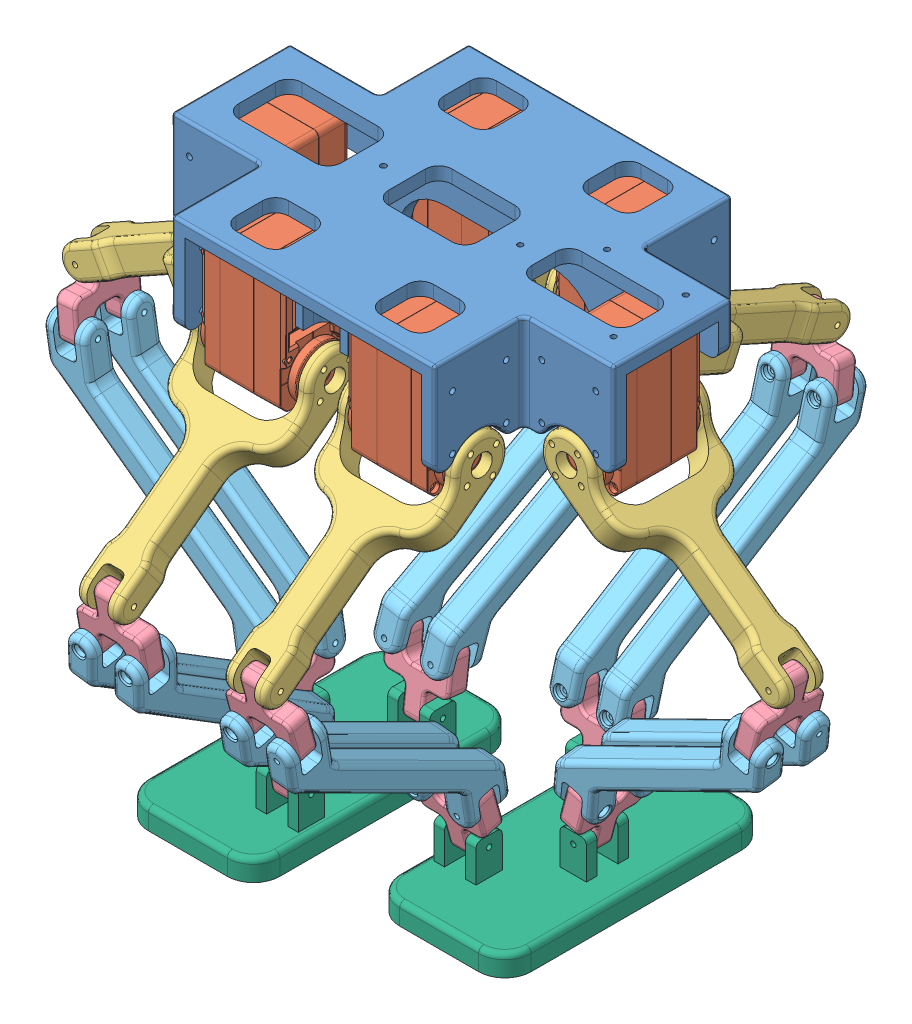
SolidWorks assembly bluebody, configuration Default. Lengths in mm.
Overall size (288.92 219.35 236.14).
42 component instances, 6 part files, 69 mates.
Components (placement in the parent):
- link0-1: link0 [Default] x (1 0 0) z (0 0 -1) size (168 59.68 113)
  - platform-v4-1: platform-v4 [Default] at (0 36.8 -17.5) x (-1 0 0) z (0 0 1) size (168 36.8 113)
  - Servo-LX-16A-1: Servo-LX-16A [Default] at (37.5 14.825 39.5) x (0 -1 0) z (0 0 1) size (54.66 37.3 26.46)
  - Servo-LX-16A-2: Servo-LX-16A [Default] at (-37.5 14.825 39.5) x (0 -1 0) z (0 0 -1) size (54.66 37.3 26.46)
  - Servo-LX-16A-3: Servo-LX-16A [Default] at (-67 14.825 -10) x (0 -1 0) z (1 0 0) size (54.66 37.3 26.46)
  - Servo-LX-16A-4: Servo-LX-16A [Default] at (-37.5 14.825 -39.5) x (0 -1 0) z (0 0 -1) size (54.66 37.3 26.46)
  - Servo-LX-16A-5: Servo-LX-16A [Default] at (37.5 14.825 -39.5) x (0 -1 0) z (0 0 1) size (54.66 37.3 26.46)
  - Servo-LX-16A-6: Servo-LX-16A [Default] at (67 14.825 -10) x (0 -1 0) z (1 0 0) size (54.66 37.3 26.46)
- link1-1: link1 [Default] at (27.9 -67.623 69.0097) x (0 0.602649 -0.798007) z (1 0 0) size (96 20 46.12)
- link1-2: link1 [Default] at (96.7069 -67.4082 0.4) x (-0.802358 0.596844 0) z (0 0 -1) size (96 20 46.12)
- link1-3: link1 [Default] at (27.9 -60.4464 -74.3013) x (0 0.411912 0.911223) z (-1 0 0) size (96 20 46.12)
- link1-4: link1 [Default] at (-27.9 -65.1405 -71.1258) x (0 0.535964 0.844241) z (-1 0 0) size (96 20 46.12)
- link1-5: link1 [Default] at (-99.9673 -63.3285 0.4) x (0.872961 0.48779 0) z (0 0 1) size (96 20 46.12)
- link1-6: link1 [Default] at (-27.9 -67.6197 69.0127) x (0 0.60256 -0.798074) z (1 0 0) size (96 20 46.12)
- link2-1: link2 [Default] at (27.9 -93.6553 100.3923) x (1 0 0) z (0 0.268825 -0.963189) size (25.2 28 7.6)
- link2-2: link2 [Default] at (128.2856 -93.2143 0.4) x (0 0 1) z (0.966195 -0.257814 0) size (25.2 28 7.6)
- link2-3: link2 [Default] at (27.9 -78.9149 -110.5714) x (1 0 0) z (0 -0.08941 -0.995995) size (25.2 28 7.6)
- link2-4: link2 [Default] at (-27.9 -88.5648 -104.657) x (1 0 0) z (0 -0.119223 -0.992868) size (25.2 28 7.6)
- link2-5: link2 [Default] at (-134.7236 -84.8335 0.4) x (0 0 -1) z (-0.99671 -0.08105 0) size (25.2 28 7.6)
- link2-6: link2 [Default] at (-27.9 -93.6878 100.5668) x (1 0 0) z (0 0.184429 -0.982846) size (25.2 28 7.6)
- link3-1: link3 [Default] at (8.3118 -142.3201 55.6635) x (0 0.268825 -0.963189) z (0.990297 -0.133854 -0.037359) size (76 94 10)
- link3-2: link3 [Default] at (25.9118 -142.3201 55.6635) x (0 -0.268825 0.963189) z (0.990297 -0.133854 -0.037359) size (76 94 10)
- link3-3: link3 [Default] at (83.7779 -143.6502 6.4272) x (-0.966195 0.257814 0) z (0.047194 0.176866 -0.983103) size (76 94 10)
- link3-4: link3 [Default] at (83.7779 -143.6502 -11.1728) x (0.966195 -0.257814 0) z (0.047194 0.176866 -0.983103) size (76 94 10)
- link3-5: link3 [Default] at (35.8148 -136.2784 -75.3013) x (0 -0.08941 -0.995995) z (-0.990297 0.138413 -0.012425) size (76 94 10)
- link3-6: link3 [Default] at (18.2148 -136.2784 -75.3013) x (0 -0.08941 -0.995995) z (-0.990297 0.138413 -0.012425) size (76 94 10)
- link3-7: link3 [Default] at (-21.2469 -144.8005 -67.6887) x (0 0.119223 0.992868) z (-0.985708 0.167261 -0.020085) size (76 94 10)
- link3-8: link3 [Default] at (-38.8469 -144.8005 -67.6887) x (0 0.119223 0.992868) z (-0.985708 0.167261 -0.020085) size (76 94 10)
- link3-9: link3 [Default] at (-99.9976 -141.7338 -16.4283) x (0.99671 0.08105 0) z (0.005869 -0.072177 0.997375) size (76 94 10)
- link3-10: link3 [Default] at (-99.9976 -141.7338 1.1717) x (0.99671 0.08105 0) z (0.005869 -0.072177 0.997375) size (76 94 10)
- link3-11: link3 [Default] at (-48.7039 -145.7078 60.2817) x (0 0.184429 -0.982846) z (0.985708 -0.165572 -0.031069) size (76 94 10)
- link3-12: link3 [Default] at (-31.1039 -145.7078 60.2817) x (0 0.184429 -0.982846) z (0.985708 -0.165572 -0.031069) size (76 94 10)
- bluefeet-1: bluefeet [Default] at (30.2265 -212.2498 -14.9766) x (0 0 -1) z (1 0 0) size (100 42.24 51.6) (flexible)
  - feet-1: feet [Default] at origin size (100 22 50)
  - link2-1: link2 [Default] at (-25.5376 19.9264 -14) x (0 0 -1) z (0.963189 0.268825 0) size (25.2 28 7.6)
  - link2-2: link2 [Default] at (0 19.9324 9.5156) x (1 0 0) z (0 -0.257814 0.966195) size (25.2 28 7.6)
  - link2-3: link2 [Default] at (25.1788 19.992 -14) x (0 0 -1) z (0.995995 -0.08941 0) size (25.2 28 7.6)
- bluefeet-2: bluefeet [Default] at (-56.0508 -219.3493 -5.6829) x (0 0 1) z (-1 0 0) size (100 42.29 51.6) (flexible)
  - feet-1: feet [Default] at origin size (100 22 50)
  - link2-1: link2 [Default] at (-25.2384 19.9857 -14) x (0 0 -1) z (0.992868 0.119223 0) size (25.2 28 7.6)
  - link2-2: link2 [Default] at (0 19.9934 9.1621) x (1 0 0) z (0 -0.08105 0.99671) size (25.2 28 7.6)
  - link2-3: link2 [Default] at (25.3689 19.9657 -14) x (0 0 -1) z (0.982846 -0.184429 0) size (25.2 28 7.6)
Mates (geometry in assembly coordinates):
- Coincident1: coincident aligned: plane of link0-1/platform-v4-1 through (0 0 17.5) normal (0 1 0)
- Coincident2: coincident anti-aligned: plane of link0-1/platform-v4-1 through (0 -36.8 17.5) normal (-1 0 0)
- Coincident4: coincident anti-aligned: plane of link0-1/platform-v4-1 through (0 -36.8 0) normal (0 0 -1)
- Concentric1: concentric aligned: cylinder of link0-1/Servo-LX-16A-5 through (46.6 -40.325 39.5) axis (1 0 0) radius 10; cylinder of link1-1 through (4.9 -40.325 39.5) axis (1 0 0) radius 4
- Distance1: distance = 0.9 mm anti-aligned: plane of link0-1/Servo-LX-16A-5 through (46 -29.3267 39.5) normal (1 0 0); plane of link1-1 through (46.9 -49.2688 82.8706) normal (-1 0 0)
- Concentric2: concentric anti-aligned: cylinder of link0-1/Servo-LX-16A-6 through (67 -40.325 -14.6) axis (0 0 1) radius 10; cylinder of link1-2 through (67 -40.325 23.4) axis (0 0 -1) radius 4
- Distance2: distance = 0.9 mm anti-aligned: plane of link1-2 through (110.4343 -48.954 -18.6) normal (0 0 1); plane of link0-1/Servo-LX-16A-6 through (86.9 -79.4276 -17.7) normal (0 0 -1)
- Concentric3: concentric anti-aligned: cylinder of link0-1/Servo-LX-16A-1 through (46.6 -40.325 -39.5) axis (1 0 0) radius 10; cylinder of link1-3 through (50.9 -40.325 -39.5) axis (-1 0 0) radius 4
- Distance3: distance = 0.9 mm anti-aligned: plane of link1-3 through (8.9 -39.4882 -83.7753) normal (1 0 0); plane of link0-1/Servo-LX-16A-1 through (9.8 -79.4276 -59.4) normal (-1 0 0)
- Concentric4: concentric aligned: cylinder of link0-1/Servo-LX-16A-2 through (-46.6 -40.325 -39.5) axis (-1 0 0) radius 10; cylinder of link1-4 through (-4.9 -40.325 -39.5) axis (-1 0 0) radius 4
- Distance4: distance = 0.9 mm anti-aligned: plane of link1-4 through (-8.9 -45.723 -83.453) normal (-1 0 0); plane of link0-1/Servo-LX-16A-2 through (-9.8 -79.4276 -19.6) normal (1 0 0)
- Concentric5: concentric aligned: cylinder of link0-1/Servo-LX-16A-3 through (-67 -40.325 19.1) axis (0 0 1) radius 10; cylinder of link1-5 through (-67 -40.325 -22.6) axis (0 0 1) radius 4
- Distance5: distance = 0.9 mm anti-aligned: plane of link1-5 through (-111.1864 -43.2503 -18.6) normal (0 0 1); plane of link0-1/Servo-LX-16A-3 through (-47.1 -79.4276 -17.7) normal (0 0 -1)
- Concentric6: concentric anti-aligned: cylinder of link1-6 through (-50.9 -40.325 39.5) axis (1 0 0) radius 4; cylinder of link0-1/Servo-LX-16A-4 through (-46.6 -40.325 39.5) axis (-1 0 0) radius 10
- Distance6: distance = 0.9 mm anti-aligned: plane of link1-6 through (-8.9 -49.264 82.8716) normal (-1 0 0); plane of link0-1/Servo-LX-16A-4 through (-9.8 -79.4276 59.4) normal (1 0 0)
- Concentric7: concentric aligned: cylinder of link1-1 through (4.9 -91.7289 100.9299) axis (1 0 0) radius 1; cylinder of link2-1 through (24.1 -91.7289 100.9299) axis (1 0 0) radius 1.15
- Distance7: distance = 0.2 mm anti-aligned: plane of link2-1 through (31.7 -94.6768 104.0524) normal (1 0 0); plane of link1-1 through (31.9 -49.2688 82.8706) normal (-1 0 0)
- Concentric8: concentric anti-aligned: cylinder of link1-2 through (128.8012 -91.2819 23.4) axis (0 0 -1) radius 1; cylinder of link2-2 through (128.8012 -91.2819 -3.4) axis (0 0 1) radius 1.15
- Distance8: distance = 0.2 mm anti-aligned: plane of link2-2 through (124.6141 -92.2346 -3.4) normal (0 0 -1); plane of link1-2 through (110.4343 -48.954 -3.6) normal (0 0 1)
- Concentric9: concentric anti-aligned: cylinder of link1-3 through (50.9 -76.9229 -110.7502) axis (-1 0 0) radius 1; cylinder of link2-3 through (24.1 -76.9229 -110.7502) axis (1 0 0) radius 1.15
- Distance9: distance = 0.2 mm anti-aligned: plane of link2-3 through (31.7 -78.5751 -106.7866) normal (1 0 0); plane of link1-3 through (31.9 -39.4882 -83.7753) normal (-1 0 0)
- Concentric10: concentric anti-aligned: cylinder of link1-4 through (-4.9 -86.579 -104.8954) axis (-1 0 0) radius 1; cylinder of link2-4 through (-31.7 -86.579 -104.8954) axis (1 0 0) radius 1.15
- Distance10: distance = 0.2 mm anti-aligned: plane of link2-4 through (-31.7 -88.1117 -100.8841) normal (-1 0 0); plane of link1-4 through (-31.9 -45.723 -83.453) normal (1 0 0)
- Concentric11: concentric anti-aligned: cylinder of link1-5 through (-134.8857 -82.8401 -22.6) axis (0 0 1) radius 1; cylinder of link2-5 through (-134.8857 -82.8401 4.2) axis (0 0 -1) radius 1.15
- Distance11: distance = 0.2 mm anti-aligned: plane of link2-5 through (-130.9361 -84.5255 -3.4) normal (0 0 -1); plane of link1-5 through (-111.1864 -43.2503 -3.6) normal (0 0 1)
- Concentric12: concentric aligned: cylinder of link1-6 through (-50.9 -91.7221 100.9356) axis (1 0 0) radius 1; cylinder of link2-6 through (-31.7 -91.7221 100.9356) axis (1 0 0) radius 1.15
- Distance12: distance = 0.2 mm anti-aligned: plane of link2-6 through (-31.7 -94.3886 104.3016) normal (-1 0 0); plane of link1-6 through (-31.9 -49.264 82.8716) normal (1 0 0)
- Concentric13: concentric aligned: cylinder of link2-1 through (19.1 -112.0142 99.2136) axis (0 0.268825 -0.963189) radius 1.15; cylinder of link3-1 through (19.1 -113.1433 103.259) axis (0 0.268825 -0.963189) radius 1
- Distance13: distance = 0.2 mm anti-aligned: plane of link3-1 through (18.2148 -152.7987 88.0383) normal (0 0.268825 -0.963189); plane of link2-1 through (27.9 -94.6768 104.0524) normal (0 -0.268825 0.963189)
- Concentric14: concentric anti-aligned: cylinder of link3-2 through (36.7 -108.8421 87.8479) axis (0 -0.268825 0.963189) radius 1; cylinder of link2-1 through (36.7 -112.0142 99.2136) axis (0 0.268825 -0.963189) radius 1.15
- Distance14: distance = 0.2 mm anti-aligned: plane of link3-2 through (35.8148 -152.7987 88.0383) normal (0 0.268825 -0.963189); plane of link2-1 through (27.9 -94.6768 104.0524) normal (0 -0.268825 0.963189)
- Concentric15: concentric anti-aligned: cylinder of link2-2 through (119.9734 -109.6261 9.2) axis (0.966195 -0.257814 0) radius 1.15; cylinder of link3-3 through (131.3745 -112.6683 9.2) axis (-0.966195 0.257814 0) radius 1
- Distance15: distance = 0.2 mm anti-aligned: plane of link3-3 through (117.1005 -150.6472 -3.4038) normal (-0.966195 0.257814 0); plane of link2-2 through (131.9571 -94.194 0.4) normal (0.966195 -0.257814 0)
- Concentric16: concentric aligned: cylinder of link2-2 through (119.9734 -109.6261 -8.4) axis (0.966195 -0.257814 0) radius 1.15; cylinder of link3-4 through (115.9154 -108.5433 -8.4) axis (0.966195 -0.257814 0) radius 1
- Distance16: distance = 0.2 mm anti-aligned: plane of link3-4 through (117.1005 -150.6472 -21.0038) normal (-0.966195 0.257814 0); plane of link2-2 through (131.9571 -94.194 0.4) normal (0.966195 -0.257814 0)
- Concentric17: concentric aligned: cylinder of link3-6 through (19.1 -96.1275 -100.9941) axis (0 -0.08941 -0.995995) radius 1; cylinder of link2-3 through (19.1 -96.503 -105.1772) axis (0 -0.08941 -0.995995) radius 1.15
- Distance17: distance = 0.2 mm anti-aligned: plane of link3-6 through (8.3118 -137.9342 -109.2893) normal (0 0.08941 0.995995); plane of link2-3 through (27.9 -79.2546 -114.3562) normal (0 -0.08941 -0.995995)
- Concentric18: concentric aligned: cylinder of link3-5 through (36.7 -96.1275 -100.9941) axis (0 -0.08941 -0.995995) radius 1; cylinder of link2-3 through (36.7 -96.503 -105.1772) axis (0 -0.08941 -0.995995) radius 1.15
- Distance18: distance = 0.2 mm anti-aligned: plane of link3-5 through (25.9118 -137.9342 -109.2893) normal (0 0.08941 0.995995); plane of link2-3 through (27.9 -79.2546 -114.3562) normal (0 -0.08941 -0.995995)
- Concentric19: concentric anti-aligned: cylinder of link2-4 through (-19.1 -105.9834 -98.7381) axis (0 -0.119223 -0.992868) radius 1.15; cylinder of link3-7 through (-19.1 -107.3902 -110.4539) axis (0 0.119223 0.992868) radius 1
- Distance19: distance = 0.2 mm anti-aligned: plane of link3-7 through (-31.1039 -146.2277 -93.7041) normal (0 -0.119223 -0.992868); plane of link2-4 through (-27.9 -88.1117 -100.8841) normal (0 0.119223 0.992868)
- Concentric20: concentric anti-aligned: cylinder of link2-4 through (-36.7 -105.9834 -98.7381) axis (0 -0.119223 -0.992868) radius 1.15; cylinder of link3-8 through (-36.7 -107.3902 -110.4539) axis (0 0.119223 0.992868) radius 1
- Distance20: distance = 0.2 mm anti-aligned: plane of link3-8 through (-48.7039 -146.2277 -93.7041) normal (0 -0.119223 -0.992868); plane of link2-4 through (-27.9 -88.1117 -100.8841) normal (0 0.119223 0.992868)
- Concentric21: concentric anti-aligned: cylinder of link2-5 through (-129.4772 -102.4663 -8.4) axis (-0.99671 -0.08105 0) radius 1.15; cylinder of link3-9 through (-141.2384 -103.4227 -8.4) axis (0.99671 0.08105 0) radius 1
- Distance21: distance = 0.2 mm anti-aligned: plane of link3-9 through (-125.8534 -144.5629 -6.4546) normal (-0.99671 -0.08105 0); plane of link2-5 through (-130.9361 -84.5255 0.4) normal (0.99671 0.08105 0)
- Concentric22: concentric anti-aligned: cylinder of link2-5 through (-129.4772 -102.4663 9.2) axis (-0.99671 -0.08105 0) radius 1.15; cylinder of link3-10 through (-141.2384 -103.4227 9.2) axis (0.99671 0.08105 0) radius 1
- Distance22: distance = 0.2 mm anti-aligned: plane of link3-10 through (-125.8534 -144.5629 11.1454) normal (-0.99671 -0.08105 0); plane of link2-5 through (-130.9361 -84.5255 0.4) normal (0.99671 0.08105 0)
- Concentric23: concentric aligned: cylinder of link2-6 through (-36.7 -112.0798 100.9819) axis (0 0.184429 -0.982846) radius 1.15; cylinder of link3-11 through (-36.7 -112.8544 105.1098) axis (0 0.184429 -0.982846) radius 1
- Distance23: distance = 0.2 mm anti-aligned: plane of link3-11 through (-38.8469 -152.1587 85.525) normal (0 -0.184429 0.982846); plane of link2-6 through (-27.9 -92.987 96.832) normal (0 0.184429 -0.982846)
- Concentric24: concentric aligned: cylinder of link2-6 through (-19.1 -112.0798 100.9819) axis (0 0.184429 -0.982846) radius 1.15; cylinder of link3-12 through (-19.1 -112.8544 105.1098) axis (0 0.184429 -0.982846) radius 1
- Distance24: distance = 0.2 mm anti-aligned: plane of link3-12 through (-21.2469 -152.1587 85.525) normal (0 -0.184429 0.982846); plane of link2-6 through (-27.9 -92.987 96.832) normal (0 0.184429 -0.982846)
- Concentric29: concentric aligned: cylinder of link3-4 through (36.6533 -172.8634 -23.7766) axis (0.966195 -0.257814 0) radius 1; cylinder of bluefeet-1/link2-2 through (40.7113 -173.9462 -23.7766) axis (0.966195 -0.257814 0) radius 1.15
- Distance26: distance = 0.2 mm anti-aligned: plane of bluefeet-1/link2-2 through (43.4137 -193.2971 -14.9766) normal (0.966195 -0.257814 0); plane of link3-4 through (59.1288 -135.1784 -21.0038) normal (-0.966195 0.257814 0)
- Concentric30: concentric anti-aligned: cylinder of link3-3 through (52.1124 -176.9884 -6.1766) axis (-0.966195 0.257814 0) radius 1; cylinder of bluefeet-1/link2-2 through (40.7113 -173.9462 -6.1766) axis (0.966195 -0.257814 0) radius 1.15
- Concentric31: concentric anti-aligned: cylinder of link3-2 through (25.0265 -172.8354 7.6944) axis (0 -0.268825 0.963189) radius 1; cylinder of bluefeet-1/link2-1 through (25.0265 -176.0076 19.0601) axis (0 0.268825 -0.963189) radius 1.15
- Distance27: distance = 0.2 mm anti-aligned: plane of link3-2 through (35.8148 -136.6692 30.247) normal (0 0.268825 -0.963189); plane of bluefeet-1/link2-1 through (16.2265 -193.345 14.2212) normal (0 -0.268825 0.963189)
- Concentric32: concentric aligned: cylinder of link3-1 through (7.4265 -177.1366 23.1054) axis (0 0.268825 -0.963189) radius 1; cylinder of bluefeet-1/link2-1 through (7.4265 -176.0076 19.0601) axis (0 0.268825 -0.963189) radius 1.15
- Concentric33: concentric aligned: cylinder of link3-5 through (25.0265 -173.6146 -33.7968) axis (0 -0.08941 -0.995995) radius 1; cylinder of bluefeet-1/link2-3 through (25.0265 -173.9902 -37.98) axis (0 -0.08941 -0.995995) radius 1.15
- Distance28: distance = 0.2 mm anti-aligned: plane of bluefeet-1/link2-3 through (16.2265 -192.5976 -43.9402) normal (0 -0.08941 -0.995995); plane of link3-5 through (25.9118 -132.5696 -49.5297) normal (0 0.08941 0.995995)
- Concentric34: concentric aligned: cylinder of link3-6 through (7.4265 -173.6146 -33.7968) axis (0 -0.08941 -0.995995) radius 1; cylinder of bluefeet-1/link2-3 through (7.4265 -173.9902 -37.98) axis (0 -0.08941 -0.995995) radius 1.15
- Concentric35: concentric anti-aligned: cylinder of link3-9 through (-74.6455 -182.0635 -14.4829) axis (0.99671 0.08105 0) radius 1; cylinder of bluefeet-2/link2-2 through (-62.8843 -181.1071 -14.4829) axis (-0.99671 -0.08105 0) radius 1.15
- Distance29: distance = 0.2 mm anti-aligned: plane of bluefeet-2/link2-2 through (-69.0004 -199.6639 -5.6829) normal (-0.99671 -0.08105 0); plane of link3-9 through (-74.0245 -140.3483 -6.4546) normal (0.99671 0.08105 0)
- Concentric36: concentric anti-aligned: cylinder of link3-10 through (-74.6455 -182.0635 3.1171) axis (0.99671 0.08105 0) radius 1; cylinder of bluefeet-2/link2-2 through (-62.8843 -181.1071 3.1171) axis (-0.99671 -0.08105 0) radius 1.15
- Concentric37: concentric aligned: cylinder of link3-8 through (-50.8508 -182.4457 -41.0103) axis (0 0.119223 0.992868) radius 1; cylinder of bluefeet-2/link2-1 through (-50.8508 -181.945 -36.8402) axis (0 0.119223 0.992868) radius 1.15
- Distance30: distance = 0.2 mm anti-aligned: plane of bluefeet-2/link2-1 through (-42.0508 -199.8166 -34.6942) normal (0 -0.119223 -0.992868); plane of link3-8 through (-48.7039 -140.0281 -42.075) normal (0 0.119223 0.992868)
- Concentric38: concentric aligned: cylinder of link3-7 through (-33.2508 -182.4457 -41.0103) axis (0 0.119223 0.992868) radius 1; cylinder of bluefeet-2/link2-1 through (-33.2508 -181.945 -36.8402) axis (0 0.119223 0.992868) radius 1.15
- Concentric39: concentric anti-aligned: cylinder of link3-11 through (-50.8508 -183.1678 30.8684) axis (0 0.184429 -0.982846) radius 1; cylinder of bluefeet-2/link2-3 through (-50.8508 -180.9916 19.2709) axis (0 -0.184429 0.982846) radius 1.15
- Distance31: distance = 0.2 mm anti-aligned: plane of link3-11 through (-38.8469 -142.5684 34.417) normal (0 0.184429 -0.982846); plane of bluefeet-2/link2-3 through (-42.0508 -200.0844 23.4208) normal (0 -0.184429 0.982846)
- Concentric40: concentric anti-aligned: cylinder of link3-12 through (-33.2508 -183.1678 30.8684) axis (0 0.184429 -0.982846) radius 1; cylinder of bluefeet-2/link2-3 through (-33.2508 -180.9916 19.2709) axis (0 -0.184429 0.982846) radius 1.15
